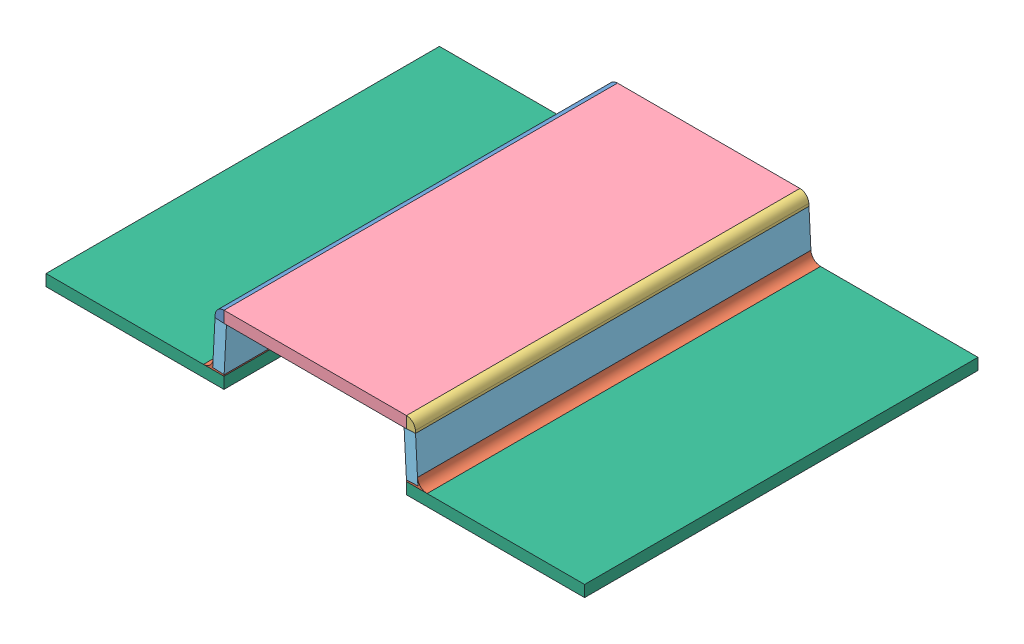
SolidWorks assembly Male mold, configuration Default. Lengths in mm.
Overall size (752.9 96 550).
17 component instances, 7 part files, 29 mates.
Components (placement in the parent):
- A4-1: A4 [Default] at (10.2322 -65.7319 557.1032) x (1 0 0) z (0 0 -1) size (12.66 15.98 550)
- A1-1: A1 [Default] at (294.0966 -133.2319 557.1032) x (-1 0 0) z (0 0 -1) size (28.69 12.79 550)
- A2-1: A2 [Default] at (265.2322 -65.7319 7.1032) x (-1 0 0) z (0 0 1) size (12.66 15.98 550)
- A1-2: A1 [Default] at (-18.6322 -133.2319 7.1032) size (28.69 12.79 550)
- P5-1: P5 [Default] at (137.7322 -69.2319 282.1032) x (1 0 0) z (0 1 0) size (255 550 16)
- P3-1: P3 [Default] at (263.5399 -100.317 282.1032) x (0 0 -1) z (0.99863 0.052336 0) size (550 61.94 16)
- P3-2: P3 [Default] at (-4.0536 -99.4805 282.1032) x (0 0 -1) z (0.99863 -0.052336 0) size (550 61.94 16)
- P6-1: P6 [Default] at (389.7916 -133.2319 282.1032) x (-1 0 0) z (0 -1 0) size (248.78 550 16)
- P6-2: P6 [Default] at (-114.3272 -133.2319 282.1032) x (1 0 0) z (0 -1 0) size (248.78 550 16)
- 90031A117_Phillips Flat Head Screws for Wood-1: 90031A117_Phillips Flat Head Screws for Wood [90031A117] at (2.0628 -133.3569 17.6032) x (0 1 0) z (0.999698 0 0.024591) size (31.75 5.71 5.71)
- 90031A117_Phillips Flat Head Screws for Wood-16: 90031A117_Phillips Flat Head Screws for Wood [90031A117] at (2.0628 -133.3569 194.1032) x (0 1 0) z (0.986419 0 -0.164247) size (31.75 5.71 5.71)
- 90031A117_Phillips Flat Head Screws for Wood-17: 90031A117_Phillips Flat Head Screws for Wood [90031A117] at (2.0628 -133.3569 370.6032) x (0 1 0) z (0.927819 0 -0.373031) size (31.75 5.71 5.71)
- 90031A117_Phillips Flat Head Screws for Wood-18: 90031A117_Phillips Flat Head Screws for Wood [90031A117] at (2.0628 -133.3569 547.1032) x (0 1 0) z (0.814513 0 -0.580145) size (31.75 5.71 5.71)
- 90031A117_Phillips Flat Head Screws for Wood-19: 90031A117_Phillips Flat Head Screws for Wood [90031A117] at (273.4016 -133.3569 17.1032) x (0 1 0) z (0.652414 0 -0.757863) size (31.75 5.71 5.71)
- 90031A117_Phillips Flat Head Screws for Wood-21: 90031A117_Phillips Flat Head Screws for Wood [90031A117] at (273.4016 -133.3569 193.6032) x (0 1 0) z (0.465534 0 -0.88503) size (31.75 5.71 5.71)
- 90031A117_Phillips Flat Head Screws for Wood-27: 90031A117_Phillips Flat Head Screws for Wood [90031A117] at (273.4016 -133.3569 370.1032) x (0 1 0) z (0.290404 0 -0.956904) size (31.75 5.71 5.71)
- 90031A117_Phillips Flat Head Screws for Wood-29: 90031A117_Phillips Flat Head Screws for Wood [90031A117] at (273.4016 -133.3569 546.6032) x (0 1 0) z (0.077293 0 -0.997008) size (31.75 5.71 5.71)
Mates (geometry in assembly coordinates):
- Coincident87: coincident aligned: plane of A4-1 through (10.2322 -65.7319 557.1032) normal (0 0 1); plane of P5-1 through (10.2322 -53.2319 557.1032) normal (0 0 1)
- Coincident107: coincident anti-aligned: plane of A4-1 through (-2.4328 -68.553 7.1032) normal (-0.052336 -0.99863 0); plane of P3-2 through (13.5453 -69.3904 557.1032) normal (0.052336 0.99863 0)
- Coincident102: coincident anti-aligned: plane of P5-1 through (265.2322 -53.2319 7.1032) normal (1 0 0); plane of A2-1 through (265.2322 -69.2167 557.1032) normal (-1 0 0)
- Coincident103: coincident aligned: plane of P5-1 through (10.2322 -53.2319 7.1032) normal (0 0 -1); plane of A2-1 through (265.2322 -65.7319 7.1032) normal (0 0 -1)
- Coincident108: coincident aligned: plane of P5-1 through (10.2322 -53.2319 7.1032) normal (0 0 -1); plane of P3-2 through (13.5453 -69.3904 7.1032) normal (0 0 -1)
- Coincident100: coincident anti-aligned: plane of P3-1 through (281.1389 -130.4072 557.1032) normal (0.052336 -0.99863 0); plane of A1-1 through (280.6166 -130.4346 7.1032) normal (-0.052336 0.99863 0)
- Coincident101: coincident aligned: plane of P3-1 through (277.8972 -68.5521 7.1032) normal (0 0 -1); plane of A1-1 through (294.0979 -119.7319 7.1032) normal (0 0 -1)
- Coincident110: coincident anti-aligned: plane of P3-2 through (-4.0536 -99.4805 282.1032) normal (-0.99863 0.052336 0); plane of A1-2 through (-5.1522 -120.4419 557.1032) normal (0.99863 -0.052336 0)
- Coincident111: coincident aligned: plane of P3-2 through (13.5453 -69.3904 7.1032) normal (0 0 -1); plane of A1-2 through (-18.6335 -119.7319 7.1032) normal (0 0 -1)
- Coincident115: coincident aligned: line of A1-2 through (10.0628 -133.2319 557.1032) axis (0 0 -1); line of P6-2 through (10.0628 -133.2319 557.1032) axis (0 0 -1)
- Coincident116: coincident aligned: line of A1-1 through (265.4016 -133.2319 7.1032) axis (0 0 1); line of P6-1 through (265.4016 -133.2319 7.1032) axis (0 0 1)
- Coincident117: coincident anti-aligned: plane of A1-1 through (294.0966 -133.2319 7.1032) normal (0 -1 0); plane of P6-1 through (389.7916 -133.2319 282.1032) normal (0 1 0)
- Coincident118: coincident aligned: plane of P3-1 through (277.8972 -68.5521 7.1032) normal (0 0 -1); plane of P6-1 through (514.1816 -149.2319 7.1032) normal (0 0 -1)
- Concentric1: concentric aligned: circle of P6-2; cylinder of 90031A117_Phillips Flat Head Screws for Wood-1 through (2.0628 -149.2319 17.6032) axis (0 -1 0) radius 1.4224
- Coincident119: coincident aligned: plane of P6-2 through (-114.3272 -149.2319 282.1032) normal (0 -1 0); plane of 90031A117_Phillips Flat Head Screws for Wood-1 through (2.0628 -149.2319 17.6032) normal (0 -1 0)
- Concentric9: concentric aligned: circle of P6-2; cylinder of 90031A117_Phillips Flat Head Screws for Wood-16 through (2.0628 -149.2319 194.1032) axis (0 -1 0) radius 1.4224
- Coincident120: coincident aligned: plane of P6-2 through (-114.3272 -149.2319 282.1032) normal (0 -1 0); plane of 90031A117_Phillips Flat Head Screws for Wood-16 through (2.0628 -149.2319 194.1032) normal (0 -1 0)
- Coincident121: coincident aligned: plane of P6-2 through (-114.3272 -149.2319 282.1032) normal (0 -1 0); plane of 90031A117_Phillips Flat Head Screws for Wood-17 through (2.0628 -149.2319 370.6032) normal (0 -1 0)
- Concentric10: concentric aligned: circle of P6-2; cylinder of 90031A117_Phillips Flat Head Screws for Wood-17 through (2.0628 -149.2319 370.6032) axis (0 -1 0) radius 1.4224
- Coincident122: coincident aligned: plane of P6-2 through (-114.3272 -149.2319 282.1032) normal (0 -1 0); plane of 90031A117_Phillips Flat Head Screws for Wood-18 through (2.0628 -149.2319 547.1032) normal (0 -1 0)
- Concentric11: concentric aligned: circle of P6-2; cylinder of 90031A117_Phillips Flat Head Screws for Wood-18 through (2.0628 -149.2319 547.1032) axis (0 -1 0) radius 1.4224
- Concentric12: concentric aligned: circle of P6-1; cylinder of 90031A117_Phillips Flat Head Screws for Wood-19 through (273.4016 -149.2319 17.1032) axis (0 -1 0) radius 1.4224
- Coincident124: coincident aligned: plane of P6-1 through (389.7916 -149.2319 282.1032) normal (0 -1 0); plane of 90031A117_Phillips Flat Head Screws for Wood-19 through (273.4016 -149.2319 17.1032) normal (0 -1 0)
- Concentric13: concentric aligned: circle of P6-1; cylinder of 90031A117_Phillips Flat Head Screws for Wood-21 through (273.4016 -149.2319 193.6032) axis (0 -1 0) radius 1.4224
- Coincident125: coincident aligned: plane of P6-1 through (389.7916 -149.2319 282.1032) normal (0 -1 0); plane of 90031A117_Phillips Flat Head Screws for Wood-21 through (273.4016 -149.2319 193.6032) normal (0 -1 0)
- Concentric16: concentric aligned: circle of P6-1; cylinder of 90031A117_Phillips Flat Head Screws for Wood-27 through (273.4016 -149.2319 370.1032) axis (0 -1 0) radius 1.4224
- Coincident134: coincident aligned: plane of P6-1 through (389.7916 -149.2319 282.1032) normal (0 -1 0); plane of 90031A117_Phillips Flat Head Screws for Wood-27 through (273.4016 -149.2319 370.1032) normal (0 -1 0)
- Concentric17: concentric aligned: circle of P6-1; cylinder of 90031A117_Phillips Flat Head Screws for Wood-29 through (273.4016 -149.2319 546.6032) axis (0 -1 0) radius 1.4224
- Coincident135: coincident aligned: plane of P6-1 through (389.7916 -149.2319 282.1032) normal (0 -1 0); plane of 90031A117_Phillips Flat Head Screws for Wood-29 through (273.4016 -149.2319 546.6032) normal (0 -1 0)
